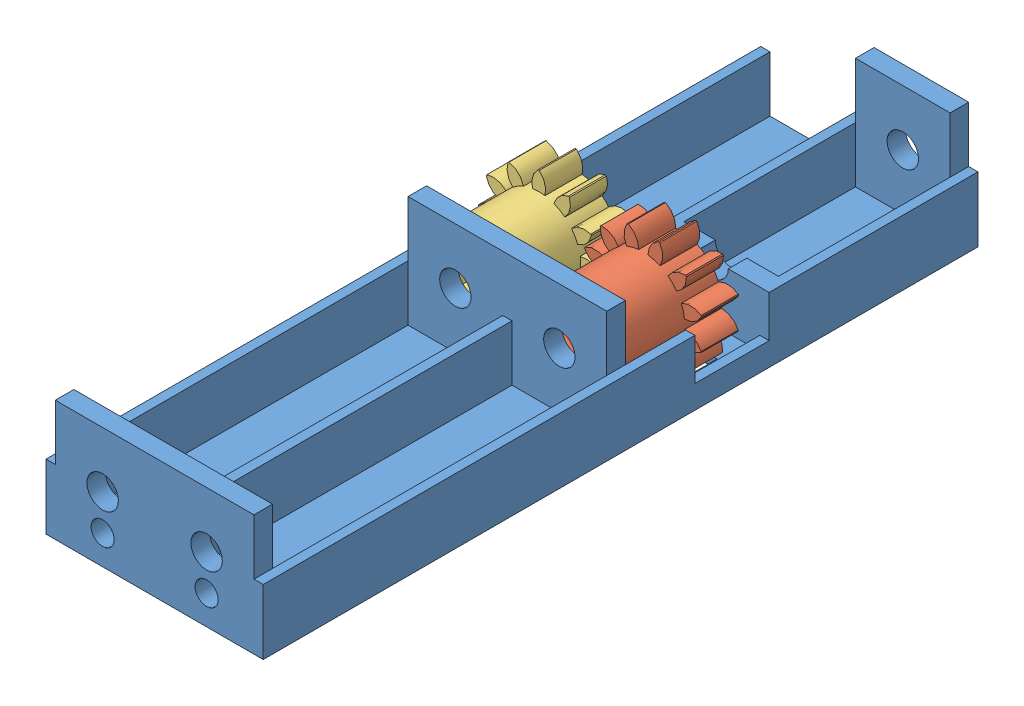
SolidWorks assembly MotorBoxAssem, configuration Default. Lengths in mm.
Overall size (27.51 17.15 77).
3 component instances, 3 part files, 4 mates.
Components (placement in the parent):
- Guide Frame - 1 Motor-1: Guide Frame - 1 Motor [Default] at (53.914 -31.3853 17.4133) size (25.4 13 77)
- 12T 13mm 3shft GearCoupler-1: 12T 13mm 3shft GearCoupler [Default] at (34.5075 45.2508 43.4133) x (0.870804 0.49163 0) z (0 0 1) size (12.59 12.59 11)
- 12T 13mm Dshft GearCoupler-1: 12T 13mm Dshft GearCoupler [Default] at (23.3075 45.2508 43.4133) x (0.262762 -0.964861 0) z (0 0 1) size (12.59 12.59 11)
Mates (geometry in assembly coordinates):
- Concentric1: concentric aligned: circle of Guide Frame - 1 Motor-1; circle of 12T 13mm Dshft GearCoupler-1
- Coincident1: coincident anti-aligned: plane of Guide Frame - 1 Motor-1 through (53.914 -31.3853 54.4133) normal (0 0 -1); plane of 12T 13mm Dshft GearCoupler-1 through (23.3075 45.2508 54.4133) normal (0 0 1)
- Concentric2: concentric anti-aligned: circle of Guide Frame - 1 Motor-1; circle of 12T 13mm 3shft GearCoupler-1
- Coincident2: coincident anti-aligned: plane of Guide Frame - 1 Motor-1 through (53.914 -31.3853 54.4133) normal (0 0 -1); plane of 12T 13mm 3shft GearCoupler-1 through (34.5075 45.2508 54.4133) normal (0 0 1)
